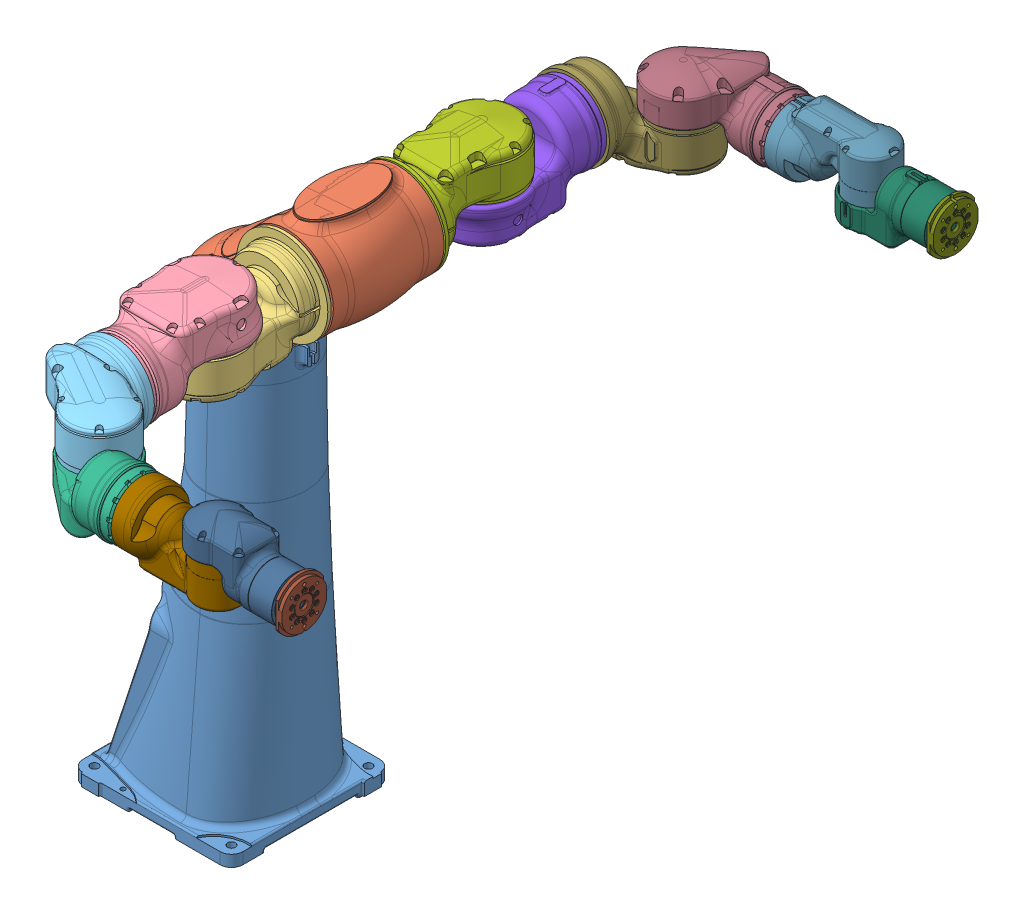
SolidWorks assembly sda5, configuration ﾃﾞﾌｫﾙﾄ. Lengths in mm.
Overall size (839.28 988.9 1253).
16 component instances, 16 part files, 30 mates.
Components (placement in the parent):
- base_link-1: base_link [ﾃﾞﾌｫﾙﾄ] at (35.8561 -341.4286 729.6002) size (283.03 729.6 283)
- torso_link-1: torso_link [ﾃﾞﾌｫﾙﾄ] at (35.8561 -342.5286 729.6002) size (329.13 319.3 224.5)
- link_r_s-1: link_r_s [ﾃﾞﾌｫﾙﾄ] at (35.8561 -342.5286 728.8502) size (160.01 160.51 208)
- link_r_l-1: link_r_l [ﾃﾞﾌｫﾙﾄ] at (35.8561 -343.2786 728.8502) size (157.25 146.29 254.29)
- link_r_e-1: link_r_e [ﾃﾞﾌｫﾙﾄ] at (35.8561 -343.2786 728.1002) size (208.5 149.27 168)
- link_r_u-1: link_r_u [ﾃﾞﾌｫﾙﾄ] at (35.8561 -342.5586 728.1002) size (201.86 131.9 172.58)
- link_l_s-1: link_l_s [ﾃﾞﾌｫﾙﾄ] at (35.8561 -342.5286 730.3502) size (160.01 160.51 208)
- link_l_l-1: link_l_l [ﾃﾞﾌｫﾙﾄ] at (35.8561 -341.7786 730.3502) size (157.25 146.29 254.29)
- link_r_r-1: link_r_r [ﾃﾞﾌｫﾙﾄ] at (35.1361 -342.5586 728.1002) size (176 121.51 105.52)
- link_r_b-1: link_r_b [ﾃﾞﾌｫﾙﾄ] at (35.1361 -342.5586 728.1002) size (184.06 114.83 92.31)
- link_r_t-2: link_r_t [ﾃﾞﾌｫﾙﾄ] at (37.1361 -342.5586 728.1002) size (14.5 89.93 78)
- link_l_e-1: link_l_e [ﾃﾞﾌｫﾙﾄ] at (35.8561 -341.7786 731.1002) size (208.5 149.27 168)
- link_l_u-1: link_l_u [ﾃﾞﾌｫﾙﾄ] at (35.8561 -342.4986 731.1002) size (201.86 131.9 172.58)
- link_l_r-1: link_l_r [ﾃﾞﾌｫﾙﾄ] at (35.1361 -342.4986 731.1002) size (176 121.51 105.52)
- link_l_b-1: link_l_b [ﾃﾞﾌｫﾙﾄ] at (35.1361 -342.4986 731.1002) size (184.06 114.83 92.31)
- link_l_t-1: link_l_t [ﾃﾞﾌｫﾙﾄ] at (34.6361 -342.4986 731.1002) size (14.5 89.93 78)
Mates (geometry in assembly coordinates):
- 同心円1: concentric anti-aligned: cylinder of base_link-1 through (35.8561 349.1714 729.6002) axis (0 1 0) radius 66; cylinder of torso_link-1 through (35.8561 451.6514 729.6002) axis (0 -1 0) radius 74.5
- 一致4: coincident anti-aligned: plane of base_link-1 through (133.8561 328.1714 906.4002) normal (0 1 0); plane of torso_link-1 through (35.8561 328.1714 729.6002) normal (0 -1 0)
- 一致7: coincident anti-aligned: plane of torso_link-1 through (185.8561 557.4714 841.8502) normal (0 0 1); plane of link_r_s-1 through (185.8561 593.2214 841.8502) normal (0 0 -1)
- 同心円3: concentric anti-aligned: cylinder of torso_link-1 through (185.8561 557.4714 747.6127) axis (0 0 1) radius 55; cylinder of link_r_s-1 through (185.8561 557.4714 829.8502) axis (0 0 -1) radius 55
- 一致8: coincident anti-aligned: plane of link_r_s-1 through (185.8561 593.2214 971.8502) normal (0 1 0); plane of link_r_l-1 through (185.8561 593.2214 1154.1002) normal (0 -1 0)
- 同心円4: concentric anti-aligned: cylinder of link_r_s-1 through (185.8561 498.9839 971.8502) axis (0 1 0) radius 55; cylinder of link_r_l-1 through (185.8561 576.2214 971.8502) axis (0 -1 0) radius 55
- 一致9: coincident anti-aligned: plane of link_r_l-1 through (185.8561 556.7214 1154.1002) normal (0 0 1); plane of link_r_e-1 through (270.8561 527.4414 1154.1002) normal (0 0 -1)
- 同心円5: concentric anti-aligned: cylinder of link_r_l-1 through (185.8561 556.7214 1059.8627) axis (0 0 1) radius 55; cylinder of link_r_e-1 through (185.8561 556.7214 1136.1002) axis (0 0 -1) radius 55
- 一致10: coincident anti-aligned: plane of link_r_e-1 through (270.8561 527.4414 1241.1002) normal (0 -1 0); plane of link_r_u-1 through (315.8561 527.4414 1241.1002) normal (0 1 0)
- 同心円6: concentric anti-aligned: cylinder of link_r_e-1 through (270.8561 614.0454 1241.1002) axis (0 -1 0) radius 45; cylinder of link_r_u-1 through (270.8561 527.4414 1241.1002) axis (0 1 0) radius 45
- 一致11: coincident anti-aligned: plane of torso_link-1 through (185.8561 557.4714 617.3502) normal (0 0 -1); plane of link_l_s-1 through (185.8561 521.7214 617.3502) normal (0 0 1)
- 同心円7: concentric anti-aligned: cylinder of torso_link-1 through (185.8561 557.4714 711.5877) axis (0 0 -1) radius 55; cylinder of link_l_s-1 through (185.8561 557.4714 629.3502) axis (0 0 1) radius 55
- 一致14: coincident anti-aligned: plane of link_l_s-1 through (185.8561 521.7214 487.3502) normal (0 -1 0); plane of link_l_l-1 through (185.8561 521.7214 305.1002) normal (0 1 0)
- 同心円10: concentric anti-aligned: cylinder of link_l_s-1 through (185.8561 615.9589 487.3502) axis (0 -1 0) radius 55; cylinder of link_l_l-1 through (185.8561 538.7214 487.3502) axis (0 1 0) radius 55
- 一致15: coincident anti-aligned: plane of link_r_u-1 through (415.1361 557.4414 1301.1002) normal (1 0 0); plane of link_r_r-1 through (415.1361 596.6414 1301.1002) normal (-1 0 0)
- 同心円11: concentric aligned: cylinder of link_r_u-1 through (412.8561 557.4414 1301.1002) axis (-1 0 0) radius 45; cylinder of link_r_r-1 through (404.1361 557.4414 1301.1002) axis (-1 0 0) radius 45
- 一致16: coincident anti-aligned: plane of link_r_r-1 through (540.1361 596.6414 1301.1002) normal (0 1 0); plane of link_r_b-1 through (679.1361 596.6414 1301.1002) normal (0 -1 0)
- 同心円12: concentric aligned: cylinder of link_r_r-1 through (540.1361 507.7064 1301.1002) axis (0 1 0) radius 40; cylinder of link_r_b-1 through (540.1361 557.4414 1301.1002) axis (0 1 0) radius 41.5
- 一致17: coincident anti-aligned: plane of link_r_b-1 through (679.1361 557.4414 1301.1002) normal (1 0 0); plane of link_r_t-2 through (679.1361 557.4414 1301.1002) normal (-1 0 0)
- 同心円13: concentric anti-aligned: cone of link_r_b-1 through (678.1361 557.4414 1301.1002) axis (1 0 0); cylinder of link_r_t-2 through (692.8861 557.4414 1301.1002) axis (-1 0 0) radius 10.5
- 一致18: coincident anti-aligned: plane of link_l_l-1 through (185.8561 558.2214 305.1002) normal (0 0 -1); plane of link_l_e-1 through (270.8561 587.5014 305.1002) normal (0 0 1)
- 同心円14: concentric anti-aligned: cylinder of link_l_l-1 through (185.8561 558.2214 399.3377) axis (0 0 -1) radius 55; cylinder of link_l_e-1 through (185.8561 558.2214 323.1002) axis (0 0 1) radius 55
- 一致19: coincident anti-aligned: plane of link_l_e-1 through (270.8561 587.5014 218.1002) normal (0 1 0); plane of link_l_u-1 through (415.1361 587.5014 158.1002) normal (0 -1 0)
- 同心円15: concentric anti-aligned: cylinder of link_l_e-1 through (270.8561 500.8974 218.1002) axis (0 1 0) radius 45; cylinder of link_l_u-1 through (270.8561 574.5014 218.1002) axis (0 -1 0) radius 45
- 一致20: coincident anti-aligned: plane of link_l_u-1 through (415.1361 557.5014 158.1002) normal (1 0 0); plane of link_l_r-1 through (415.1361 518.3014 158.1002) normal (-1 0 0)
- 同心円16: concentric anti-aligned: cylinder of link_l_u-1 through (328.5321 557.5014 158.1002) axis (1 0 0) radius 45; cylinder of link_l_r-1 through (404.1361 557.5014 158.1002) axis (-1 0 0) radius 45
- 一致21: coincident anti-aligned: plane of link_l_r-1 through (540.1361 518.3014 158.1002) normal (0 -1 0); plane of link_l_b-1 through (679.1361 518.3014 158.1002) normal (0 1 0)
- 同心円17: concentric aligned: cylinder of link_l_r-1 through (540.1361 607.2364 158.1002) axis (0 -1 0) radius 40; cylinder of link_l_b-1 through (540.1361 557.5014 158.1002) axis (0 -1 0) radius 41.5
- 一致22: coincident anti-aligned: plane of link_l_b-1 through (676.6361 557.5014 158.1002) normal (1 0 0); plane of link_l_t-1 through (676.6361 557.5014 158.1002) normal (-1 0 0)
- 同心円18: concentric anti-aligned: cylinder of link_l_b-1 through (590.2011 557.5014 158.1002) axis (1 0 0) radius 26.5; cylinder of link_l_t-1 through (690.3861 557.5014 158.1002) axis (-1 0 0) radius 10.5
